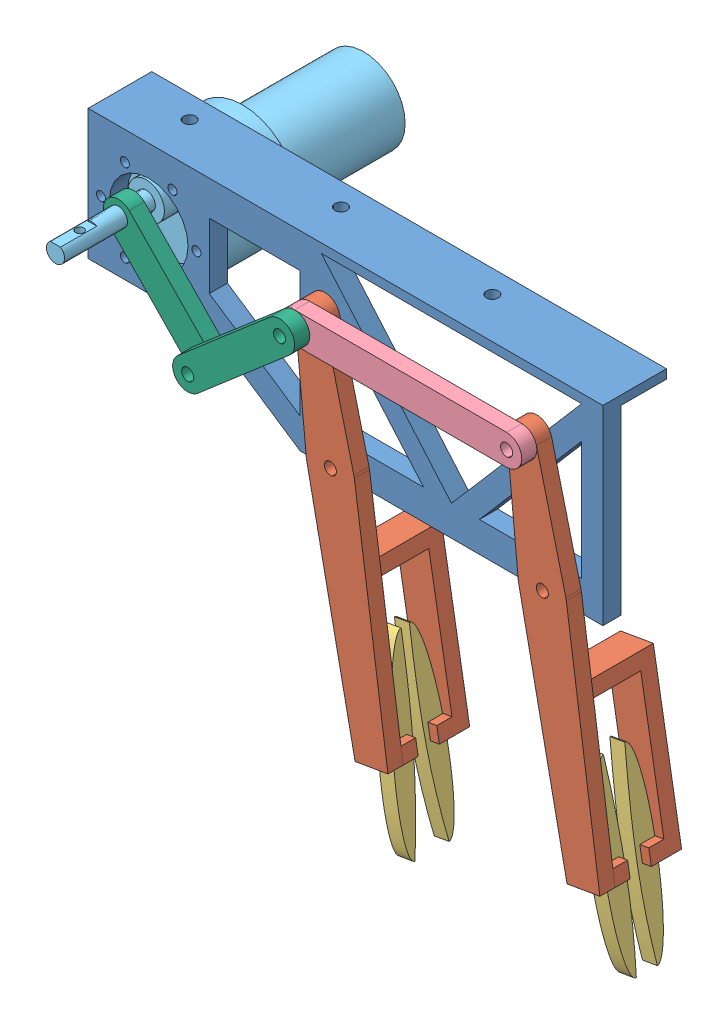
SolidWorks assembly Wiper, configuration Default. Lengths in mm.
Overall size (176.48 164.61 101.8).
11 component instances, 6 part files, 13 mates.
Components (placement in the parent):
- Wiper_Stand-1: Wiper_Stand [Default] at (93.9903 63.6345 142.3821) x (1 0 0) z (0 0 -1) size (170 63 21)
- Wiper_Arm-2-1: Wiper_Arm-2 [Default] at (61.9636 46.3889 142.3821) x (0.985461 0.169904 0) z (0 0 1) size (16 125 27)
- Wiper_Arm-2-2: Wiper_Arm-2 [Default] at (131.9636 46.3889 142.3821) x (0.985461 0.169904 0) z (0 0 1) size (16 125 27)
- Wiper Blade-1: Wiper Blade [Default] at (69.5515 17.0927 131.8559) x (-0.985461 -0.169904 0) z (-0.008364 0.048514 -0.998788) size (5 60 6.62)
- Wiper Blade-2: Wiper Blade [Default] at (64.6588 16.0424 134.5988) x (0.985461 0.169904 0) z (-0.015825 0.091785 0.995653) size (5 60 6.62)
- Wiper Blade-3: Wiper Blade [Default] at (139.5287 17.2252 130.6663) x (-0.985461 -0.169904 0) z (-0.00161 0.00934 -0.999955) size (5 60 6.62)
- Wiper Blade-4: Wiper Blade [Default] at (134.5926 16.4265 137.7236) x (0.985461 0.169904 0) z (0.001933 -0.011212 0.999935) size (5 60 6.62)
- Part8^Wiper-1: Part8^Wiper [Default] at (16.9971 -46.7818 147.3821) size (80 10 5) (virtual)
- DC motor-1: DC motor [Default] at (-6.0097 98.6345 136.3821) x (-1 0 0) z (0 0 -1) size (37 37 101.8)
- Part9^Wiper-1: Part9^Wiper [Default] at (69.7094 78.7455 152.3821) x (0.751741 0.659458 0) z (0 0 1) size (50 10.37 5) (virtual)
- Part9^Wiper-2: Part9^Wiper [Default] at (-1.323 57.9991 147.3821) x (0.703831 -0.710367 0) z (0 0 1) size (50 10.37 5) (virtual)
Mates (geometry in assembly coordinates):
- Coincident1: coincident: circle of Wiper_Arm-2-1; circle of Wiper Blade-1
- Coincident2: coincident: circle of Wiper_Arm-2-1; circle of Wiper Blade-2
- Coincident3: coincident: circle of Wiper_Arm-2-2; circle of Wiper Blade-3
- Coincident4: coincident: circle of Wiper_Arm-2-2; circle of Wiper Blade-4
- Coincident6: coincident: circle of Wiper_Stand-1; circle of Wiper_Arm-2-1
- Coincident7: coincident: circle of Wiper_Stand-1; circle of Wiper_Arm-2-2
- Coincident8: coincident: circle of Wiper_Arm-2-1; circle of Part8^Wiper-1
- Coincident9: coincident: circle of Wiper_Arm-2-2; circle of Part8^Wiper-1
- Coincident10: coincident: circle of Wiper_Stand-1; circle of DC motor-1
- Coincident11: coincident: circle of Wiper_Stand-1; circle of DC motor-1
- Coincident12: coincident: circle of Part8^Wiper-1; circle of Part9^Wiper-1
- Coincident13: coincident: circle of Part9^Wiper-1; circle of Part9^Wiper-2
- Concentric1: concentric: cylinder of DC motor-1 through (-6.0097 105.6345 173.1821) axis (0 0 -1) radius 3; cylinder of Part9^Wiper-2 through (-6.0097 105.6345 152.3821) axis (0 0 -1) radius 2
